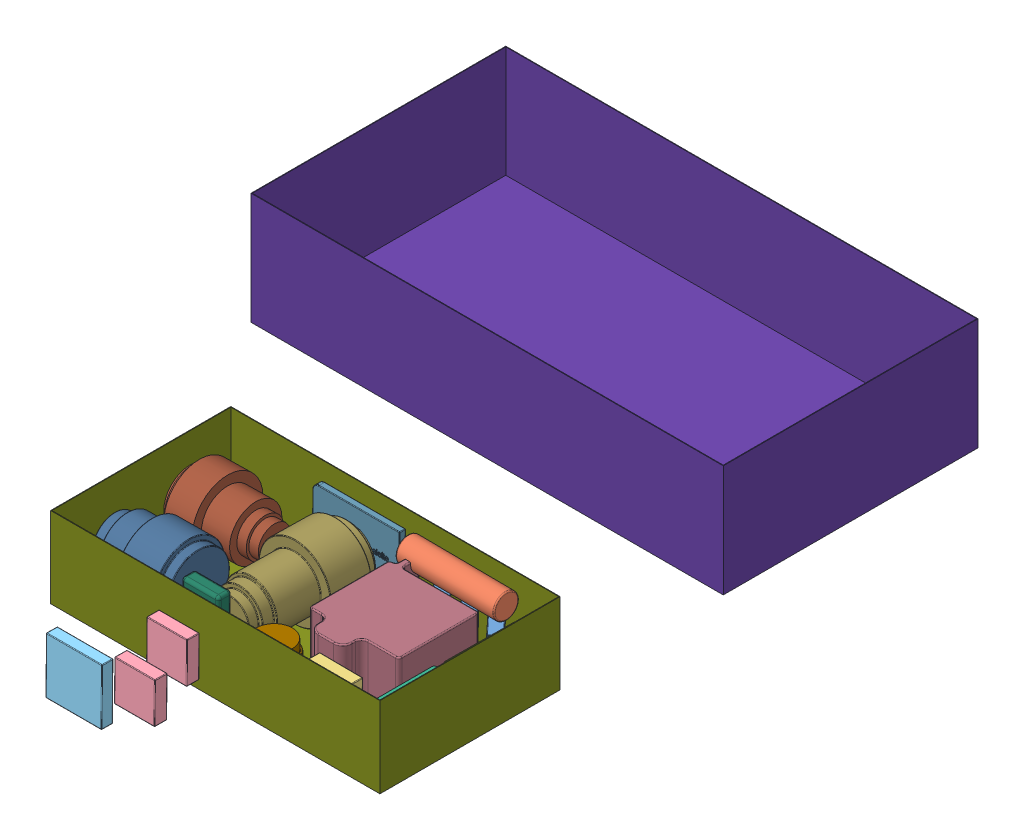
SolidWorks assembly test luggage #1, configuration Default. Lengths in mm.
Overall size (783.33 436.76 863.97).
20 component instances, 17 part files, 0 mates.
Components (placement in the parent):
- battery nikon EN-EL 15-6: battery nikon EN-EL 15 [Default] at (452.9739 -302.7896 -144.0734) x (0.694658 0 0.71934) z (0.006277 0.999962 -0.006062) size (40 20 55)
- battery nikon EN-EL 15-7: battery nikon EN-EL 15 [Default] at (496.7074 -302.9332 -144.4234) x (0.681998 0 0.731354) z (0.006382 0.999962 -0.005951) size (40 20 55)
- battery nikon EN-EL 15-8: battery nikon EN-EL 15 [Default] at (540.1661 -303.4491 -144.0869) x (0.681998 0 0.731354) z (0.006382 0.999962 -0.005951) size (40 20 55)
- charger power cable cylinder-1: charger power cable cylinder [Default] at (578.5033 -268.0906 -135.8332) x (-0.008727 0 0.999962) z (-0.999962 0 -0.008727) size (40 40 160)
- nikhon charger MH-25A-1: nikhon charger MH-25A [Default] at (489.3231 -270.3205 108.7027) x (0.999962 0 0.008727) z (0.000076 0.999962 -0.008726) size (70 33 95)
- lens filters-1: lens filters [Default] at (315.7435 -320.6018 161.1055) x (1 0 0) z (0 -0.999962 0.008727) size (65 20 65)
- nikon T2 lens converter-1: nikon T2 lens converter [Default] at (249.002 -354.0137 258.4186) x (1 0 0) z (0 -0.999962 0.008727) size (90 18 90)
- lens filters-2: lens filters [Default] at (320.7121 -345.886 217.8129) x (1 0 0) z (0 -0.999962 0.008727) size (65 20 65)
- meike remote cable-1: meike remote cable [Default] at (599.0355 -292.4603 -5.7045) size (30 30 110)
- meike remote control 110x30x20-1: meike remote control 110x30x20 [Default] at (599.5333 -291.9967 -21.6222) x (1 0 0) z (0 0.999962 -0.008727) size (20 110 30)
- shoot remote control 195x40x45-1: shoot remote control 195x40x45 [Default] at (599.0695 -341.4356 -85.5921) x (0.999962 -0.008726 0) z (-0.008726 -0.999962 -0.000076) size (35 195 50)
- nikkor AF 50mm F1_8-1: nikkor AF 50mm F1_8 [Default] at (415.032 -295.4381 74.3989) size (80 113.9 65)
- nikkor AF-S 20mm 1_8G ED-1: nikkor AF-S 20mm 1_8G ED [Default] at (206.0156 -308.3027 43.6095) x (0 0 -1) z (0.008727 -0.999962 0) size (115 135.07 115)
- nikkor AFS 24-120mm F4_0 VR ED-1: nikkor AFS 24-120mm F4_0 VR ED [Default] at (175.8548 -317.564 -85.9423) x (0.008798 -0.008255 0.999927) z (0.008654 -0.999928 -0.008331) size (115 135 115)
- nikkor AFS 24-70mm F2_8 VRII ED-1: nikkor AFS 24-70mm F2_8 VRII ED [Default] at (334.8521 -307.0559 -16.8995) x (-0.000076 -0.999962 0.008726) z (0.999962 0 0.008727) size (117 190.11 117)
- nikon D750 body + meike MK DR-750-1: nikon D750 body + meike MK DR-750 [Default] at (509.5785 -354.9828 -37.1248) x (0 0 1) z (-1 0 0) size (190 90 145)
- prodisk II color palette-1: prodisk II color palette [Default] at (315.6236 -257.0313 -152.0865) x (1 0 0) z (0 -0.999962 0.008727) size (140 10 100)
- SD case-1: SD case [Default] at (296.0048 -364.2334 84.3258) x (0 0.999962 -0.008727) z (1 0 0) size (122 22 60)
- pelican 1535 (inside 530x290x130)-1: pelican 1535 (inside 530x290x130) [Default] at (327.31 -373.5508 -77.7215) size (530 130 290)
- pelican 1615 (inside 760x410x180)-1: pelican 1615 (inside 760x410x180) [Default] at (350.641 -119.2662 -496.9713) size (760 180 410)
